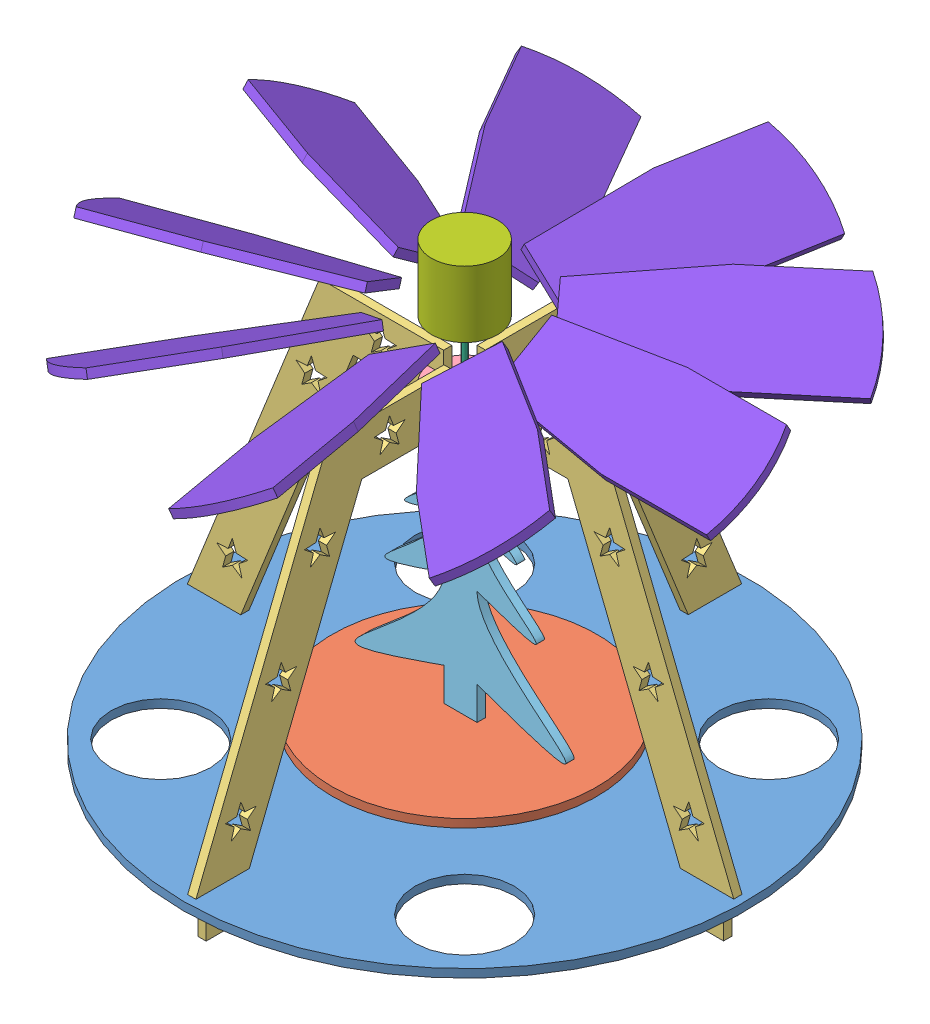
SolidWorks assembly Assembly, configuration Default. Lengths in mm.
Overall size (228.55 182.17 231.32).
19 component instances, 8 part files, 13 mates.
Components (placement in the parent):
- Base-1: Base [Default] at (98.3765 117.9321 152.7598) size (215.9 3.17 215.9)
- Rotating_Base-1: Rotating_Base [Default] at (98.3765 127.4571 152.7598) size (101.6 3.17 101.6)
- Support_Legs-1: Support_Legs [Default] at (-6.4951 117.9321 154.4108) x (1 0 0) z (0 -1 0) size (98.42 3.17 142.88)
- Support_Legs-2: Support_Legs [Default] at (100.0275 117.9321 257.6313) x (0 0 -1) z (0 -1 0) size (98.42 3.17 142.88)
- Support_Legs-3: Support_Legs [Default] at (203.248 117.9321 151.1088) x (-1 0 0) z (0 -1 0) size (98.42 3.17 142.88)
- Support_Legs-4: Support_Legs [Default] at (96.7255 117.9321 47.8883) x (0 0 1) z (0 -1 0) size (98.42 3.17 142.88)
- Top_Center_Spindle_Support-1: Top_Center_Spindle_Support [Default] at (98.3765 236.7406 152.7598) size (25.4 3.17 25.4)
- Tree-1: Tree [Default] at (98.3765 114.7571 154.3473) x (1 0 0) z (0 -1 0) size (81.7 3.17 88.9)
- Rod-1: Rod [Default] at (98.3765 124.2821 152.7598) size (2 146.05 2)
- Fan_Hub-1: Fan_Hub [Default] at (98.3765 258.828 152.7598) size (25.4 25.4 25.4)
- Fan_Blades-2: Fan_Blades [Default] at (212.6765 261.3261 155.7254) x (1 0 0) z (0 -0.499144 0.866519) size (89 3.17 38.1)
- Fan_Blades-11: Fan_Blades [Default] at (187.8416 261.3261 81.561) x (0.766044 0 -0.642788) z (0.556988 -0.499144 0.663792) size (89 3.17 38.1)
- Fan_Blades-12: Fan_Blades [Default] at (121.145 261.3261 40.7113) x (0.173648 0 -0.984808) z (0.853355 -0.499144 0.150469) size (89 3.17 38.1)
- Fan_Blades-13: Fan_Blades [Default] at (43.7947 261.3261 52.2903) x (-0.5 0 -0.866025) z (0.750428 -0.499144 -0.43326) size (89 3.17 38.1)
- Fan_Blades-14: Fan_Blades [Default] at (-8.0161 261.3261 110.8802) x (-0.939693 0 -0.34202) z (0.296367 -0.499144 -0.814262) size (89 3.17 38.1)
- Fan_Blades-15: Fan_Blades [Default] at (-10.0447 261.3261 189.066) x (-0.939693 0 0.34202) z (-0.296367 -0.499144 -0.814262) size (89 3.17 38.1)
- Fan_Blades-16: Fan_Blades [Default] at (38.6582 261.3261 250.2637) x (-0.5 0 0.866025) z (-0.750428 -0.499144 -0.43326) size (89 3.17 38.1)
- Fan_Blades-17: Fan_Blades [Default] at (115.3039 261.3261 265.8383) x (0.173648 0 0.984808) z (-0.853355 -0.499144 0.150469) size (89 3.17 38.1)
- Fan_Blades-18: Fan_Blades [Default] at (184.0291 261.3261 228.5022) x (0.766044 0 0.642788) z (-0.556988 -0.499144 0.663792) size (89 3.17 38.1)
Mates (geometry in assembly coordinates):
- Coincident2: coincident: line of Base-1 through (-2.5885 117.9321 151.1088) axis (0 0 1); line of Support_Legs-1 through (-2.5885 117.9321 151.2358) axis (0 0 1)
- Coincident3: coincident: point of Base-1; point of Support_Legs-1
- Concentric1: concentric aligned: circle of Base-1; circle of Rotating_Base-1
- Coincident6: coincident anti-aligned: plane of Support_Legs-1 through (91.9299 236.7406 151.2358) normal (0 -1 0); plane of Top_Center_Spindle_Support-1 through (98.3765 236.7406 152.7598) normal (0 1 0)
- Distance1: distance = 6.35 mm anti-aligned: plane of Rotating_Base-1 through (98.3765 124.2821 152.7598) normal (0 -1 0); plane of Base-1 through (98.3765 117.9321 152.7598) normal (0 1 0)
- Coincident8: coincident anti-aligned: plane of Rotating_Base-1 through (98.3765 127.4571 152.7598) normal (0 1 0); plane of Tree-1 through (92.0265 127.4571 151.1723) normal (0 -1 0)
- Concentric2: concentric: cylinder of Rotating_Base-1 through (98.3765 124.2821 152.7598) axis (0 1 0) radius 1.125; moEndPointRef_w of Tree-1
- Concentric3: concentric aligned: circle of Rotating_Base-1; circle of Rod-1
- Coincident12: coincident aligned: plane of Rotating_Base-1 through (98.3765 124.2821 152.7598) normal (0 -1 0); plane of Rod-1 through (98.3765 124.2821 152.7598) normal (0 -1 0)
- Concentric4: concentric anti-aligned: cylinder of Rod-1 through (98.3765 270.3321 152.7598) axis (0 -1 0) radius 1; circle of Fan_Hub-1
- Distance2: distance = 22.0874 mm anti-aligned: plane of Fan_Hub-1 through (98.3765 258.828 152.7598) normal (0 -1 0); plane of Top_Center_Spindle_Support-1 through (98.3765 236.7406 152.7598) normal (0 1 0)
- Distance6: distance = 12.7 mm anti-aligned: plane of Fan_Blades-2 through (123.7765 252.2357 165.1454) normal (-1 0 0); cylinder of Fan_Hub-1 through (98.3765 284.228 152.7598) axis (0 -1 0) radius 12.7
- Distance8: distance = 16.51 mm: plane of Fan_Blades-2 through (151.9087 259.6198 158.6875) normal (0 0.866519 0.499144); line of Support_Legs-3 through (104.823 244.9321 151.1088) axis (1 0 0)
